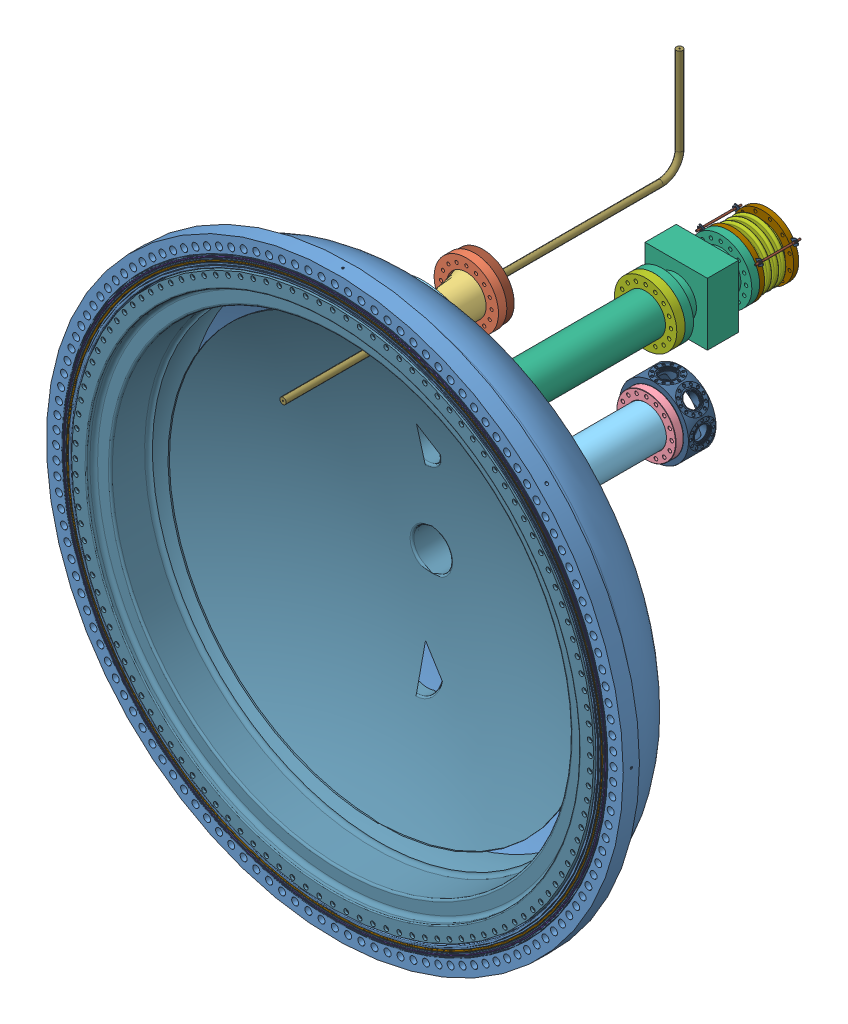
SolidWorks assembly energy_head_assem_jordi, configuration Predeterminado. Lengths in mm.
Overall size (1480 1536.09 1251.86).
83 component instances, 32 part files, 0 mates.
Components (placement in the parent):
- head_assem-1: head_assem [Predeterminado] at (0 0 200.4) size (1480 1536.09 1251.86)
  - NUT_m8-FT-1: NUT_m8-FT [Predeterminado] at (0 315.1256 -1334.0565) x (1 0 0) z (0 -1 0) size (13 6.97 15.01)
  - pin_retainer-1: pin_retainer [Predeterminado] at (38.5373 38.5373 -1) x (0.707107 -0.707107 0) z (0 0 1) size (1 13 1)
  - pin_retainer-2: pin_retainer [Predeterminado] at (38.5373 -38.5373 -1) x (-0.707107 -0.707107 0) z (0 0 1) size (1 13 1)
  - pin_retainer-3: pin_retainer [Predeterminado] at (-38.5373 -38.5373 -1) x (-0.707107 0.707107 0) z (0 0 1) size (1 13 1)
  - pin_retainer-4: pin_retainer [Predeterminado] at (-38.5373 38.5373 -1) x (0.707107 0.707107 0) z (0 0 1) size (1 13 1)
  - extension_nozzle_axial-1: extension_nozzle_axial [Predeterminado] at (0 0 -30) size (160 160 390)
    - flange_aux.1.1.1-1: flange_aux.1.1.1 [Predeterminado] at (0 250 -70.85) x (1 0 0) z (0 0 -1) size (160 160 21.44)
    - flange_CF_6in-1: flange_CF_6in [Predeterminado] at (0 0 -1730.1451) x (-1 0 0) z (0 0 -1) size (151.64 151.64 19.81)
    - tube_1-1: tube_1 [Predeterminado] at (0 0 -242.4894) size (101.85 101.85 368.46)
  - extension_nozzle_aux_l.1-1: extension_nozzle_aux_l.1 [Predeterminado] at (0 0 -30) size (160 160 400)
    - flange_aux.1.1.1-1: flange_aux.1.1.1 [Predeterminado] at (0 500 -60.85) x (1 0 0) z (0 0 -1) size (160 160 21.44)
    - nozzle_auxiliary_1-1: nozzle_auxiliary_1 [Predeterminado] at (0 250 -242.8779) size (101.85 101.85 378.46)
    - flange_aux_3-1: flange_aux_3 [Predeterminado] at (0 0 -439.4114) x (-1 0 0) z (0 0 -1) size (160 160 21.44)
  - O-ring_H2o-1: O-ring_H2o [Predeterminado] at (0 0 -203.9) x (0.998854 0.047854 0) z (0 0 -1) size (1392 1392 2.61)
  - O-ring_press.1.1-1: O-ring_press.1.1 [Predeterminado] at (0 0 -203.5) x (0.998854 0.047854 0) z (0 0 -1) size (1377.4 1377.4 3.81)
  - KIMBALL_OCTAGON_MCF600-SO200800-C-1: KIMBALL_OCTAGON_MCF600-SO200800-C [Predeterminado] at (0 0 -1795.4511) x (0 0 -1) z (1 0 0) size (190.37 186.76 190.37)
  - hv_feedthrough_assem.aux-1: hv_feedthrough_assem.aux [Predeterminado] at (0 522.0886 -179.1996) size (160 354 1025.39)
    - flange_aux.1-1: flange_aux.1 [Predeterminado] at (0 -250 148.3496) x (-1 0 0) z (0 0 -1) size (160 160 21.44)
    - tefzel-1: tefzel [Predeterminado] at (0 -250 149.1996) size (16.2 282.1 1025.39)
  - head_weldment.1-1: head_weldment.1 [Predeterminado] at (0 0 -282.8) x (-1 0 0) z (0 0 -1) size (1480 1510.05 550.83)
    - reinforcement.axial.1.1.1-1: reinforcement.axial.1.1.1 [Predeterminado] at (0 -13.7355 -284.0742) x (1 0 0) z (0 0.183956 -0.982934) size (203.29 202.99 30.7)
    - nozzle_aux_l.2-1: nozzle_aux_l.2 [Predeterminado] at (0 0 -282.8) x (1 0 0) z (0 0 -1) size (165 165 21.44)
      - flange_aux_2-1: flange_aux_2 [Predeterminado] at (0 0 -69.4114) x (-1 0 0) z (0 0 -1) size (165 165 21.44)
    - nozzle_axial-1: nozzle_axial [Predeterminado] at (0 0 -282.8) x (-1 0 0) z (0 0 -1) size (165 165 85.73)
      - flange_1-1: flange_1 [Predeterminado] at (0 250 -79.4114) x (1 0 0) z (0 0 -1) size (165 165 21.44)
      - tube-1: tube [Predeterminado] at (0 0 -242.4894) size (101.6 101.6 74.63)
    - nozzle_aux_l-1: nozzle_aux_l [Predeterminado] at (0 0 -282.8) x (-1 0 0) z (0 0 -1) size (440 939.85 440)
      - nozzle_auxiliary.1-1: nozzle_auxiliary.1 [Predeterminado] at (0 -250 -242.8779) x (-1 0 0) z (0 0 1) size (440 440 440)
      - nozzle_auxiliary.1-2: nozzle_auxiliary.1 [Predeterminado] at (0 250 -242.8779) size (440 440 440)
      - flange_aux_1-1: flange_aux_1 [Predeterminado] at (0 0 -69.4114) x (-1 0 0) z (0 0 -1) size (165 165 21.44)
    - head_O_ring-1: head_O_ring [Predeterminado] at (0 0 -17.4) x (-1 0 0) z (0 0 -1) size (1480 1480 359.44)
    - nozzle_hv-1: nozzle_hv [Predeterminado] at (0 272.0886 -282.8) x (-1 0 0) z (0 0 -1) size (496.82 496.82 496.82)
      - flange_aux-1: flange_aux [Predeterminado] at (0 0 -9.4114) x (-1 0 0) z (0 0 -1) size (165 165 21.44)
      - nozzle_auxiliary-1: nozzle_auxiliary [Predeterminado] at (0 250 217.1221) size (496.82 496.82 496.82)
    - reinforcement.axial-1: reinforcement.axial [Predeterminado] at (0 0 -282.8) x (-1 0 0) z (0 0 -1) size (203.28 203.96 19.57)
    - reinforcement.axial.1.1.1-2: reinforcement.axial.1.1.1 [Predeterminado] at (0 13.7355 -284.0742) x (-1 0 0) z (0 -0.183956 -0.982934) size (203.29 202.99 30.7)
    - reinforcement.axial.1.2-1: reinforcement.axial.1.2 [Predeterminado] at (0 28.6873 -288.5308) x (-1 0 0) z (0 -0.384203 -0.923249) size (193.14 205.75 36.46)
  - pr_valve-1: pr_valve [Predeterminado] at (0 500 -3050.8787) x (-1 0 0) z (0 0 1) size (160 160 191)
  - Expansion_joint_DN_300-24-1: Expansion_joint_DN_300-24 [Predeterminado] at (0 409.091 -2872.1834) x (0 0 -1) z (1 0 0) size (116.37 226.64 225.59)
    - Bellows_x_3-1: Bellows_x_3 [Predeterminado] at (-867.7643 -159.091 0) x (0 0 1) z (-1 0 0) size (152 152 98.91)
    - Skirt-1: Skirt [Predeterminado] at (-843.2202 -159.091 0) x (0 0 -1) z (-1 0 0) size (150.73 123.2 81.91)
    - Flange_with_bracket-1: Flange_with_bracket [Predeterminado] at origin size (12.82 174.55 171.94)
      - Flange-1: Flange [Predeterminado] at (-921.0383 -159.091 0) size (12.82 160 160)
      - Bracket.2-1: Bracket.2 [Predeterminado] at (-916.6747 -239.0909 0) x (0 0 -1) z (0 -1 0) size (16.36 1.45 14.55)
      - Bracket.2-2: Bracket.2 [Predeterminado] at (-915.2201 -119.091 -69.282) x (0 -0.866025 -0.5) z (0 0.5 -0.866025) size (16.36 1.45 14.55)
      - Bracket.2-3: Bracket.2 [Predeterminado] at (-915.2201 -119.091 69.282) x (0 0.866025 -0.5) z (0 0.5 0.866025) size (16.36 1.45 14.55)
    - Flange_with_bracket-2: Flange_with_bracket [Predeterminado] at (-1741.7131 -238.6365 -137.7768) x (-1 0 0) z (0 -0.866025 0.5) size (12.82 174.55 171.94)
      - Flange-1: Flange [Predeterminado] at (-921.0383 -159.091 0) size (12.82 160 160)
      - Bracket.2-1: Bracket.2 [Predeterminado] at (-916.6747 -239.0909 0) x (0 0 -1) z (0 -1 0) size (16.36 1.45 14.55)
      - Bracket.2-2: Bracket.2 [Predeterminado] at (-915.2201 -119.091 -69.282) x (0 -0.866025 -0.5) z (0 0.5 -0.866025) size (16.36 1.45 14.55)
      - Bracket.2-3: Bracket.2 [Predeterminado] at (-915.2201 -119.091 69.282) x (0 0.866025 -0.5) z (0 0.5 0.866025) size (16.36 1.45 14.55)
    - Fixation_bolt.2-1: Fixation_bolt.2 [Predeterminado] at (300 -240 0) x (0 0 -1) z (0 1 0) size (8.73 116.37 8.73)
      - Pin_bolt-1: Pin_bolt [Predeterminado] at (0 1111.9475 -6.3636) size (4.37 116.37 4.37)
      - Flat_washer_12_mm.3-1: Flat_washer_12_mm.3 [Predeterminado] at (0 1125.0384 -6.3636) x (0 0 -1) z (0 1 0) size (8.73 8.73 0.91)
      - Flat_washer_12_mm.3-2: Flat_washer_12_mm.3 [Predeterminado] at (0 1122.6748 -6.3636) x (0 0 1) z (0 1 0) size (8.73 8.73 0.91)
      - Flat_washer_12_mm.3-3: Flat_washer_12_mm.3 [Predeterminado] at (0 1215.2201 -6.3636) x (0 0 -1) z (0 -1 0) size (8.73 8.73 0.91)
      - Flat_washer_12_mm.3-4: Flat_washer_12_mm.3 [Predeterminado] at (0 1217.5838 -6.3636) x (0 0 -1) z (0 -1 0) size (8.73 8.73 0.91)
      - Flat_nut_M12.2-1: Flat_nut_M12.2 [Predeterminado] at (0 1125.9475 -6.3636) x (0 -1 0) z (0 0 1) size (2.64 6.55 8.08)
      - Flat_nut_M12.2-2: Flat_nut_M12.2 [Predeterminado] at (0 1122.6748 -6.3636) x (0 1 0) z (0 0 1) size (2.64 6.55 8.08)
      - Flat_nut_M12.2-3: Flat_nut_M12.2 [Predeterminado] at (0 1214.311 -6.3636) x (0 1 0) z (0 0 1) size (2.64 6.55 8.08)
      - Flat_nut_M12.2-4: Flat_nut_M12.2 [Predeterminado] at (0 1217.5838 -6.3636) x (0 -1 0) z (0 0 1) size (2.64 6.55 8.08)
    - Fixation_bolt.2-2: Fixation_bolt.2 [Predeterminado] at (300 -118.6365 -70.0692) x (0 0.866025 0.5) z (0 -0.5 0.866025) size (8.73 116.37 8.73)
      - Pin_bolt-1: Pin_bolt [Predeterminado] at (0 1111.9475 -6.3636) size (4.37 116.37 4.37)
      - Flat_washer_12_mm.3-1: Flat_washer_12_mm.3 [Predeterminado] at (0 1125.0384 -6.3636) x (0 0 -1) z (0 1 0) size (8.73 8.73 0.91)
      - Flat_washer_12_mm.3-2: Flat_washer_12_mm.3 [Predeterminado] at (0 1122.6748 -6.3636) x (0 0 1) z (0 1 0) size (8.73 8.73 0.91)
      - Flat_washer_12_mm.3-3: Flat_washer_12_mm.3 [Predeterminado] at (0 1215.2201 -6.3636) x (0 0 -1) z (0 -1 0) size (8.73 8.73 0.91)
      - Flat_washer_12_mm.3-4: Flat_washer_12_mm.3 [Predeterminado] at (0 1217.5838 -6.3636) x (0 0 -1) z (0 -1 0) size (8.73 8.73 0.91)
      - Flat_nut_M12.2-1: Flat_nut_M12.2 [Predeterminado] at (0 1125.9475 -6.3636) x (0 -1 0) z (0 0 1) size (2.64 6.55 8.08)
      - Flat_nut_M12.2-2: Flat_nut_M12.2 [Predeterminado] at (0 1122.6748 -6.3636) x (0 1 0) z (0 0 1) size (2.64 6.55 8.08)
      - Flat_nut_M12.2-3: Flat_nut_M12.2 [Predeterminado] at (0 1214.311 -6.3636) x (0 1 0) z (0 0 1) size (2.64 6.55 8.08)
      - Flat_nut_M12.2-4: Flat_nut_M12.2 [Predeterminado] at (0 1217.5838 -6.3636) x (0 -1 0) z (0 0 1) size (2.64 6.55 8.08)
    - Fixation_bolt.2-3: Fixation_bolt.2 [Predeterminado] at (300 -110.4258 79.4798) x (0 0.612776 -0.790257) z (0 0.790257 0.612776) size (8.73 116.37 8.73)
      - Pin_bolt-1: Pin_bolt [Predeterminado] at (0 1111.9475 -6.3636) size (4.37 116.37 4.37)
      - Flat_washer_12_mm.3-1: Flat_washer_12_mm.3 [Predeterminado] at (0 1125.0384 -6.3636) x (0 0 -1) z (0 1 0) size (8.73 8.73 0.91)
      - Flat_washer_12_mm.3-2: Flat_washer_12_mm.3 [Predeterminado] at (0 1122.6748 -6.3636) x (0 0 1) z (0 1 0) size (8.73 8.73 0.91)
      - Flat_washer_12_mm.3-3: Flat_washer_12_mm.3 [Predeterminado] at (0 1215.2201 -6.3636) x (0 0 -1) z (0 -1 0) size (8.73 8.73 0.91)
      - Flat_washer_12_mm.3-4: Flat_washer_12_mm.3 [Predeterminado] at (0 1217.5838 -6.3636) x (0 0 -1) z (0 -1 0) size (8.73 8.73 0.91)
      - Flat_nut_M12.2-1: Flat_nut_M12.2 [Predeterminado] at (0 1125.9475 -6.3636) x (0 -1 0) z (0 0 1) size (2.64 6.55 8.08)
      - Flat_nut_M12.2-2: Flat_nut_M12.2 [Predeterminado] at (0 1122.6748 -6.3636) x (0 1 0) z (0 0 1) size (2.64 6.55 8.08)
      - Flat_nut_M12.2-3: Flat_nut_M12.2 [Predeterminado] at (0 1214.311 -6.3636) x (0 1 0) z (0 0 1) size (2.64 6.55 8.08)
      - Flat_nut_M12.2-4: Flat_nut_M12.2 [Predeterminado] at (0 1217.5838 -6.3636) x (0 -1 0) z (0 0 1) size (2.64 6.55 8.08)
  - shield_head-1: shield_head [Predeterminado] at origin size (1342.71 1394.62 471.89)
